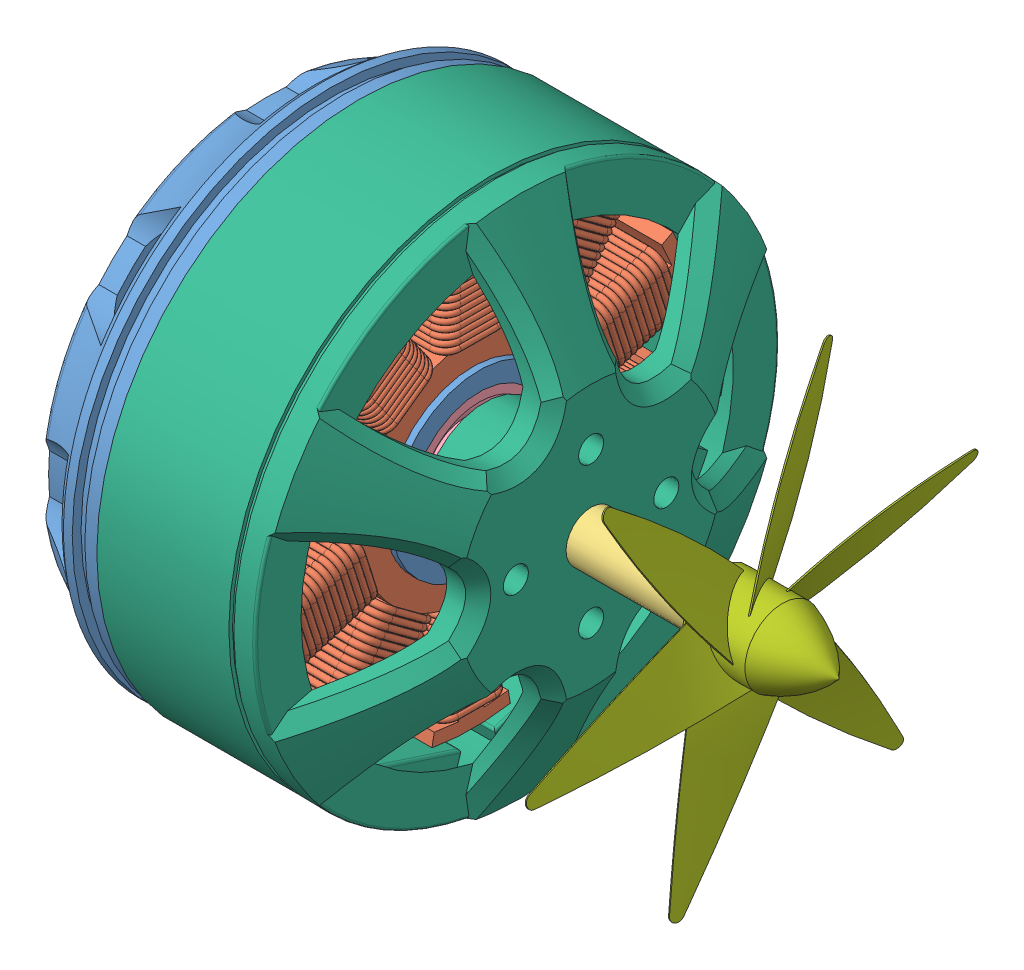
SolidWorks assembly Assem1 bldc completed, configuration Default. Lengths in mm.
Overall size (46.5 46.31 45.08).
8 component instances, 7 part files, 14 mates.
Components (placement in the parent):
- Part2-1: Part2 [Default] at (-12.9824 21.0347 42.6339) size (17.23 41.32 41.32)
- Part3-1: Part3 [Default] at (3.5176 21.0347 42.6339) x (0 -0.953376 -0.301786) z (0 0.301786 -0.953376) size (35.65 8.95 36)
- Part4-1: Part4 [Default] at (-13.7824 21.0347 42.6339) x (0 0.470647 -0.882321) z (0 -0.882321 -0.470647) size (4 42.02 4.05)
- radial ball bearing_68_skf-1: radial ball bearing_68_skf [SKF - 604 - 8,SI,NC,8_68] at (2.0176 21.0347 42.6339) x (-1 0 0) z (0 0.408879 -0.912589) size (4 12 12)
- radial ball bearing_68_skf-5: radial ball bearing_68_skf [SKF - 604 - 8,SI,NC,8_68] at (-10.9824 21.0347 42.6339) x (-1 0 0) z (0 -0.824102 -0.566442) size (4 12 12)
- Part6-1: Part6 [Default] at (-12.9824 21.0347 42.6339) x (0 0.798299 0.602261) z (0 -0.602261 0.798299) size (5 0.2 4.79)
- Part1`-1: Part1` [Default] at (12.9476 21.0347 42.6339) size (18.53 41.8 41.8)
- Part5-1: Part5 [Default] at (25.7176 21.0347 42.6339) x (0 0.941349 -0.337433) z (0 -0.337433 -0.941349) size (36.76 9.5 34.68)
Mates (geometry in assembly coordinates):
- Concentric1: concentric anti-aligned: cylinder of Part2-1 through (-12.9824 21.0347 42.6339) axis (-1 0 0) radius 7; cylinder of Part3-1 through (-4.4824 21.0347 42.6339) axis (1 0 0) radius 7
- Coincident1: coincident anti-aligned: plane of Part2-1 through (-4.4824 29.0347 42.6339) normal (1 0 0); plane of Part3-1 through (-4.4824 21.0347 42.6339) normal (-1 0 0)
- Concentric2: concentric aligned: cylinder of Part2-1 through (-12.9824 21.0347 42.6339) axis (-1 0 0) radius 1; cylinder of Part4-1 through (28.2176 21.0347 42.6339) axis (-1 0 0) radius 2
- Concentric4: concentric aligned: cylinder of Part4-1 through (28.2176 21.0347 42.6339) axis (-1 0 0) radius 2; cylinder of radial ball bearing_68_skf-1 through (22.6551 21.0347 42.6339) axis (-1 0 0) radius 2
- Coincident2: coincident anti-aligned: plane of Part2-1 through (0.0176 22.0347 42.6339) normal (1 0 0); plane of radial ball bearing_68_skf-1 through (0.0176 23.0424 43.5334) normal (-1 0 0)
- Concentric7: concentric aligned: cylinder of Part4-1 through (28.2176 21.0347 42.6339) axis (-1 0 0) radius 2; cylinder of radial ball bearing_68_skf-5 through (9.6551 21.0347 42.6339) axis (-1 0 0) radius 2
- Coincident3: coincident aligned: circle of Part4-1; plane of radial ball bearing_68_skf-5 through (-12.9824 22.2809 40.8209) normal (-1 0 0)
- Concentric8: concentric anti-aligned: cylinder of Part4-1 through (28.2176 21.0347 42.6339) axis (-1 0 0) radius 2; circle of Part6-1
- Coincident4: coincident anti-aligned: plane of radial ball bearing_68_skf-5 through (-12.9824 22.2809 40.8209) normal (-1 0 0); plane of Part6-1 through (-12.9824 22.4682 41.9231) normal (1 0 0)
- Coincident5: coincident aligned: plane of Part2-1 through (-12.9824 26.5347 42.6339) normal (-1 0 0); plane of radial ball bearing_68_skf-5 through (-12.9824 24.3201 37.8541) normal (-1 0 0)
- Concentric9: concentric: cylinder of Part4-1 through (28.2176 21.0347 42.6339) axis (-1 0 0) radius 2; point of Part1`-1
- Coincident7: coincident anti-aligned: plane of Part2-1 through (-5.5824 41.6922 42.6339) normal (1 0 0); plane of Part1`-1 through (-5.5824 21.0347 42.6339) normal (-1 0 0)
- Concentric10: concentric aligned: cylinder of Part4-1 through (28.2176 21.0347 42.6339) axis (-1 0 0) radius 2; cylinder of Part5-1 through (28.2176 21.0347 42.6339) axis (-1 0 0) radius 3
- Coincident8: coincident aligned: circle of Part4-1; circle of Part5-1
